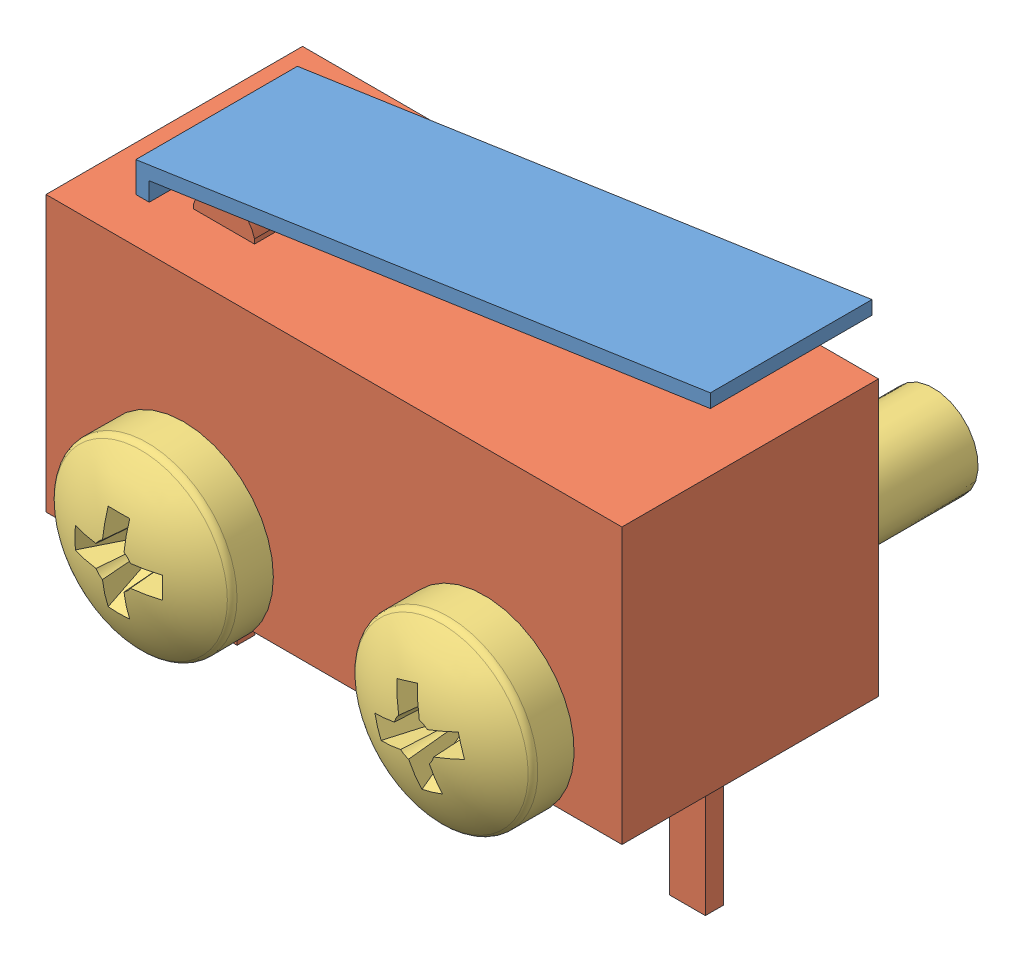
SolidWorks assembly Endstop assembly, configuration Default. Lengths in mm.
Overall size (13.8 11.8 11.57).
5 component instances, 3 part files, 4 mates.
Components (placement in the parent):
- Endstop Assembly (HT-010-1A-250VAC) - small-1: Endstop Assembly (HT-010-1A-250VAC) - small [Default] at (-0.8242 -1.9413 1.4759) size (13.8 11.8 5.71)
  - Endstop Actuator (HT-010-1A-250VAC)-1: Endstop Actuator (HT-010-1A-250VAC) [Default] at (-9.3436 7.5264 -0.1798) size (12.8 2.57 3.6)
  - Enstop Base (HT-010-1A-250VAC)-1: Enstop Base (HT-010-1A-250VAC) [Default] at (-1.4636 2.6194 0.1552) size (12.83 9.86 5.71)
- pan head cross recess screw_iso1-1: pan head cross recess screw_iso1 [ISO 7045 - M2 x 10 - Z --- 10N] at (-2.2029 0.4551 6.0461) x (0 0 -1) z (-0.957289 -0.289133 0) size (11.57 4 4)
- pan head cross recess screw_iso1-3: pan head cross recess screw_iso1 [ISO 7045 - M2 x 10 - Z --- 10N] at (-8.9029 0.4551 6.0461) x (0 0 -1) z (1 0 0) size (11.57 4 4)
Mates (geometry in assembly coordinates):
- Concentric4005641: concentric aligned: cylinder of Endstop Assembly (HT-010-1A-250VAC) - small-1/Enstop Base (HT-010-1A-250VAC)-1 through (-2.2029 0.4551 -16.3539) axis (0 0 1) radius 0.95; cylinder of pan head cross recess screw_iso-1 through (-2.2029 0.4551 31.4461) axis (0 0 1) radius 2
- Coincident78718721: coincident anti-aligned: plane of Endstop Assembly (HT-010-1A-250VAC) - small-1/Enstop Base (HT-010-1A-250VAC)-1 through (-11.9679 5.3051 4.4461) normal (0 0 1); plane of pan head cross recess screw_iso-1 through (-1.9137 -0.5022 4.4461) normal (0 0 -1)
- Concentric4005642: concentric aligned: cylinder of Endstop Assembly (HT-010-1A-250VAC) - small-1/Enstop Base (HT-010-1A-250VAC)-1 through (-8.9029 0.4551 -16.3539) axis (0 0 1) radius 0.95; cylinder of pan head cross recess screw_iso-3 through (-8.9029 0.4551 31.4461) axis (0 0 1) radius 2
- Coincident78718722: coincident anti-aligned: plane of Endstop Assembly (HT-010-1A-250VAC) - small-1/Enstop Base (HT-010-1A-250VAC)-1 through (-11.9679 5.3051 4.4461) normal (0 0 1); plane of pan head cross recess screw_iso-3 through (-8.9029 1.4551 4.4461) normal (0 0 -1)
